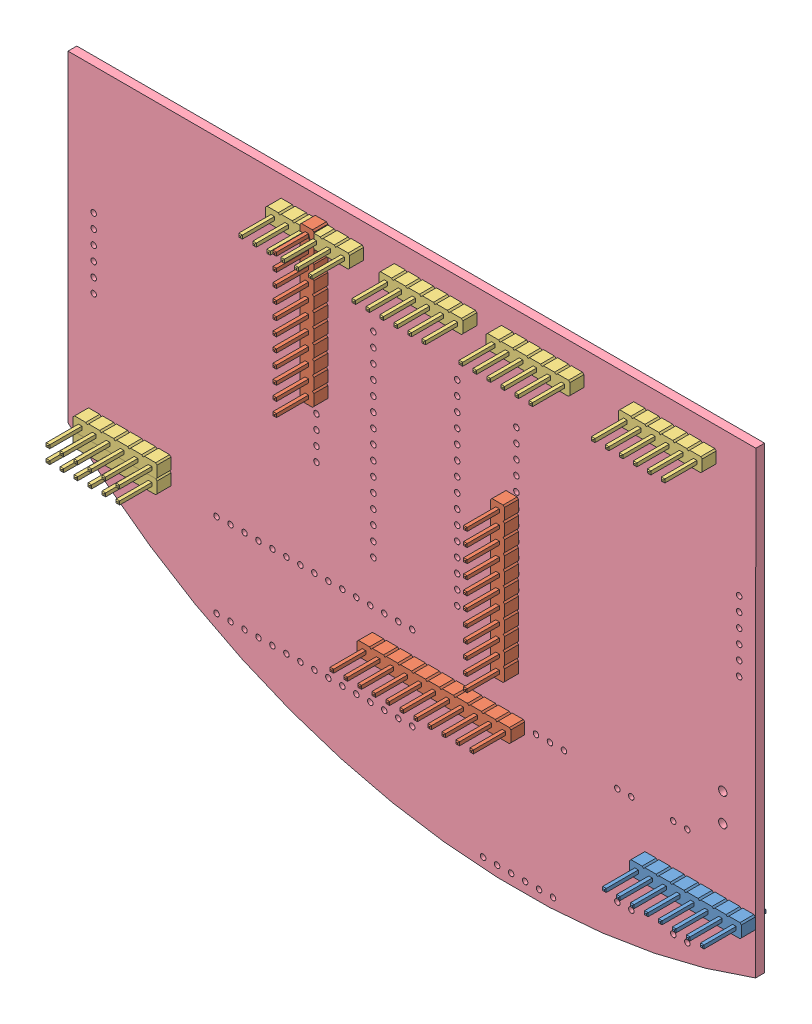
SolidWorks assembly mike_pcb_motors, configuration Default. Lengths in mm.
Overall size (125 91.12 11.54).
22 component instances, 4 part files, 0 mates.
Components (placement in the parent):
- mike_pcb_motors.step-1: mike_pcb_motors.step [Default] at origin size (125 91.12 11.54)
  - PinHeader_1x08_P2.54mm_Vertical.step-1: PinHeader_1x08_P2.54mm_Vertical.step [Default] at (173.92 -193.28 1.65) x (0 1 0) z (0 0 1) size (2.54 20.32 11.54)
    - SOLID.step-1: SOLID.step [Default] at origin size (2.54 20.32 11.54)
  - PinHeader_1x11_P2.54mm_Vertical.step-1: PinHeader_1x11_P2.54mm_Vertical.step [Default] at (148.66 -149.08 1.65) size (2.54 27.94 11.54)
    - SOLID-0.step-1: SOLID-0.step [Default] at origin size (2.54 27.94 11.54)
  - PinHeader_1x11_P2.54mm_Vertical.step-2: PinHeader_1x11_P2.54mm_Vertical.step [Default] at (114 -148.5 1.65) x (-1 0 0) z (0 0 1) size (2.54 27.94 11.54)
    - SOLID-0.step-1: SOLID-0.step [Default] at origin size (2.54 27.94 11.54)
  - PinHeader_1x11_P2.54mm_Vertical.step-3: PinHeader_1x11_P2.54mm_Vertical.step [Default] at (149.79 -183.535 1.65) x (0 -1 0) z (0 0 1) size (2.54 27.94 11.54)
    - SOLID-0.step-1: SOLID-0.step [Default] at origin size (2.54 27.94 11.54)
  - PinHeader_1x06_P2.54mm_Vertical.step-1: PinHeader_1x06_P2.54mm_Vertical.step [Default] at (184.58 -123.5 1.65) x (0 -1 0) z (0 0 1) size (2.54 15.24 11.54)
    - SOLID-1.step-1: SOLID-1.step [Default] at origin size (2.54 15.24 11.54)
  - PinHeader_1x06_P2.54mm_Vertical.step-2: PinHeader_1x06_P2.54mm_Vertical.step [Default] at (85.5 -176.5 1.65) x (0 -1 0) z (0 0 1) size (2.54 15.24 11.54)
    - SOLID-1.step-1: SOLID-1.step [Default] at origin size (2.54 15.24 11.54)
  - PinHeader_1x06_P2.54mm_Vertical.step-3: PinHeader_1x06_P2.54mm_Vertical.step [Default] at (85.5 -174 1.65) x (0 -1 0) z (0 0 1) size (2.54 15.24 11.54)
    - SOLID-1.step-1: SOLID-1.step [Default] at origin size (2.54 15.24 11.54)
  - PinHeader_1x06_P2.54mm_Vertical.step-4: PinHeader_1x06_P2.54mm_Vertical.step [Default] at (120.5 -123.5 1.65) x (0 -1 0) z (0 0 1) size (2.54 15.24 11.54)
    - SOLID-1.step-1: SOLID-1.step [Default] at origin size (2.54 15.24 11.54)
  - PinHeader_1x06_P2.54mm_Vertical.step-5: PinHeader_1x06_P2.54mm_Vertical.step [Default] at (141.08 -123.5 1.65) x (0 -1 0) z (0 0 1) size (2.54 15.24 11.54)
    - SOLID-1.step-1: SOLID-1.step [Default] at origin size (2.54 15.24 11.54)
  - PinHeader_1x06_P2.54mm_Vertical.step-6: PinHeader_1x06_P2.54mm_Vertical.step [Default] at (160.54 -123.5 1.65) x (0 -1 0) z (0 0 1) size (2.54 15.24 11.54)
    - SOLID-1.step-1: SOLID-1.step [Default] at origin size (2.54 15.24 11.54)
  - COMPOUND.step-1: COMPOUND.step [Default] at origin size (125 91.12 1.6)
